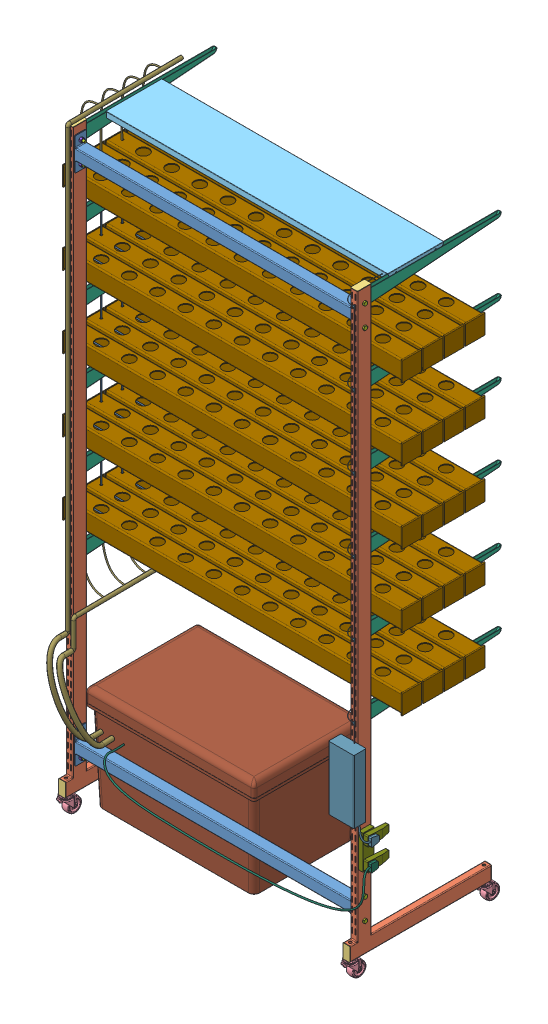
SolidWorks assembly C-L-1000, configuration Default. Lengths in mm.
Overall size (1206 2127.7 609.52).
90 component instances, 16 part files, 241 mates.
Components (placement in the parent):
- TB-1000-1: TB-1000 [Default] at (0 2029.5 0) size (985 115 40)
- TB-1000-2: TB-1000 [Default] at (0 205.5 0) size (985 115 40)
- TSU-F-L-P-1: TSU-F-L-P [Default] at (505 113.5 -25) size (25 2050 500)
- TSU-F-L-P-2: TSU-F-L-P [Default] at (-505 113.5 -25) size (25 2050 500)
- TSU-CAP-1: TSU-CAP [Default] at (-505.1 113.6 -39.9) x (-1 0 0) z (0 0 -1) size (25.2 50.2 6.5)
- TSU-CAP-2: TSU-CAP [Default] at (504.9 113.6 -39.9) x (-1 0 0) z (0 0 -1) size (25.2 50.2 6.5)
- TSU-CAP-3: TSU-CAP [Default] at (505.1 1703.4 -25.1) x (1 0 0) z (0 1 0) size (25.2 50.2 6.5)
- TSU-CAP-4: TSU-CAP [Default] at (504.9 113.6 -360.1) size (25.2 50.2 6.5)
- TSU-CAP-5: TSU-CAP [Default] at (-504.9 1703.4 -25.1) x (1 0 0) z (0 1 0) size (25.2 50.2 6.5)
- TSU-CAP-6: TSU-CAP [Default] at (-504.9 113.6 -360.1) size (25.2 50.2 6.5)
- 2834T320_THREADED-STEM SWIVEL CASTER-1: 2834T320_THREADED-STEM SWIVEL CASTER [2834T32] at (505 82.55 -437.5) x (0 0 -1) z (1 0 0) size (67.73 101.87 56.07)
- 2834T320_THREADED-STEM SWIVEL CASTER-2: 2834T320_THREADED-STEM SWIVEL CASTER [2834T32] at (-505 82.55 37.5) x (0 0 -1) z (1 0 0) size (67.73 101.87 56.07)
- 2834T320_THREADED-STEM SWIVEL CASTER-3: 2834T320_THREADED-STEM SWIVEL CASTER [2834T32] at (505 82.55 37.5) x (0 0 -1) z (1 0 0) size (67.73 101.87 56.07)
- 2834T320_THREADED-STEM SWIVEL CASTER-4: 2834T320_THREADED-STEM SWIVEL CASTER [2834T32] at (-505 82.55 -437.5) x (0 0 -1) z (1 0 0) size (67.73 101.87 56.07)
- TSS-1000-10: TSS-1000 [Default] at (0 818 -199.337) size (1014.96 37.01 331.17)
- TSUB-1: TSUB [Default] at (505 766.5 -25) x (-1 0 0) z (0 0 -1) size (14.07 50.86 484.03)
- TSUB-2: TSUB [Default] at (-505 766.5 -25) x (-1 0 0) z (0 0 -1) size (14.07 50.86 484.03)
- TSUB-3: TSUB [Default] at (-505 1022.5 -25) x (-1 0 0) z (0 0 -1) size (14.07 50.86 484.03)
- TSUB-4: TSUB [Default] at (505 1022.5 -25) x (-1 0 0) z (0 0 -1) size (14.07 50.86 484.03)
- TSS-1000-9: TSS-1000 [Default] at (0 1074 -199.337) size (1014.96 37.01 331.17)
- TSUB-5: TSUB [Default] at (-505 1534.5 -25) x (-1 0 0) z (0 0 -1) size (14.07 50.86 484.03)
- TSUB-6: TSUB [Default] at (505 1534.5 -25) x (-1 0 0) z (0 0 -1) size (14.07 50.86 484.03)
- TSS-1000-3: TSS-1000 [Default] at (0 1586 -199.337) size (1014.96 37.01 331.17)
- TSUB-7: TSUB [Default] at (-505 2046.5 -25) x (-1 0 0) z (0 0 -1) size (14.07 50.86 484.03)
- TSUB-8: TSUB [Default] at (505 2046.5 -25) x (-1 0 0) z (0 0 -1) size (14.07 50.86 484.03)
- TSS-1000-7: TSS-1000 [Default] at (0 2098 -199.337) size (1014.96 37.01 331.17)
- TSUB-9: TSUB [Default] at (-505 1278.5 -25) x (-1 0 0) z (0 0 -1) size (14.07 50.86 484.03)
- TSUB-10: TSUB [Default] at (505 1278.5 -25) x (-1 0 0) z (0 0 -1) size (14.07 50.86 484.03)
- TSS-1000-8: TSS-1000 [Default] at (0 1330 -199.337) size (1014.96 37.01 331.17)
- TSUB-11: TSUB [Default] at (-505 1790.5 -25) x (-1 0 0) z (0 0 -1) size (14.07 50.86 484.03)
- TSUB-12: TSUB [Default] at (505 1790.5 -25) x (-1 0 0) z (0 0 -1) size (14.07 50.86 484.03)
- TSS-1000-6: TSS-1000 [Default] at (0 1842 -199.337) size (1014.96 37.01 331.17)
- hex bolt gradeab2_bsi-10: hex bolt gradeab2_bsi [BS EN 28765 - M8x1 x 45 x 22-N] at (522.8 2067 0) x (-1 0 0) z (0 -0.924225 -0.381849) size (50.3 15.01 13)
- hex bolt gradeab2_bsi-11: hex bolt gradeab2_bsi [BS EN 28765 - M8x1 x 45 x 22-N] at (522.8 1992 0) x (-1 0 0) z (0 -0.999974 0.007224) size (50.3 15.01 13)
- hex bolt gradeab2_bsi-12: hex bolt gradeab2_bsi [BS EN 28765 - M8x1 x 45 x 22-N] at (-522.8 2067 0) size (50.3 15.01 13)
- hex bolt gradeab2_bsi-13: hex bolt gradeab2_bsi [BS EN 28765 - M8x1 x 45 x 22-N] at (-522.8 1992 0) size (50.3 15.01 13)
- hex bolt gradeab2_bsi-14: hex bolt gradeab2_bsi [BS EN 28765 - M8x1 x 45 x 22-N] at (-522.8 168 0) size (50.3 15.01 13)
- hex bolt gradeab2_bsi-15: hex bolt gradeab2_bsi [BS EN 28765 - M8x1 x 45 x 22-N] at (-522.8 243 0) size (50.3 15.01 13)
- hex bolt gradeab2_bsi-16: hex bolt gradeab2_bsi [BS EN 28765 - M8x1 x 45 x 22-N] at (522.8 168 0) x (-1 0 0) z (0 0.924225 0.381849) size (50.3 15.01 13)
- hex bolt gradeab2_bsi-17: hex bolt gradeab2_bsi [BS EN 28765 - M8x1 x 45 x 22-N] at (522.8 243 0) x (-1 0 0) z (0 -0.924225 -0.381849) size (50.3 15.01 13)
- hex nut gradec_bsi-1: hex nut gradec_bsi [BS EN 24034 - M8 - N] at (481.6 2067 0) x (0 0 1) z (-1 0 0) size (13 15.01 7.9)
- hex nut gradec_bsi-2: hex nut gradec_bsi [BS EN 24034 - M8 - N] at (481.6 1992 0) x (0 0 1) z (-1 0 0) size (13 15.01 7.9)
- hex nut gradec_bsi-3: hex nut gradec_bsi [BS EN 24034 - M8 - N] at (-481.6 2067 0) x (0 0 -1) z (1 0 0) size (13 15.01 7.9)
- hex nut gradec_bsi-4: hex nut gradec_bsi [BS EN 24034 - M8 - N] at (-481.6 1992 0) x (0 0.383049 0.923728) z (1 0 0) size (13 15.01 7.9)
- hex nut gradec_bsi-5: hex nut gradec_bsi [BS EN 24034 - M8 - N] at (-481.6 243 0) x (0 0 -1) z (1 0 0) size (13 15.01 7.9)
- hex nut gradec_bsi-6: hex nut gradec_bsi [BS EN 24034 - M8 - N] at (481.6 243 0) x (0 0 1) z (-1 0 0) size (13 15.01 7.9)
- hex nut gradec_bsi-7: hex nut gradec_bsi [BS EN 24034 - M8 - N] at (481.6 168 0) x (0 0 1) z (-1 0 0) size (13 15.01 7.9)
- hex nut gradec_bsi-8: hex nut gradec_bsi [BS EN 24034 - M8 - N] at (-481.6 168 0) x (0 0 -1) z (1 0 0) size (13 15.01 7.9)
- GB-1000-b-30: GB-1000-b [Default] at (0 1106.5 -233.1077) size (1206 70 70)
- GB-600-p-1: GB-600-p [Default] at (-200 1106.5 -233.1077) size (92 218.31 4)
- GB-600-p-2: GB-600-p [Default] at (-200 1106.5 -308.1077) size (92 218.31 4)
- GB-1000-b-29: GB-1000-b [Default] at (0 1106.5 -308.1077) size (1206 70 70)
- GB-600-p-3: GB-600-p [Default] at (-200 1106.5 -83.1077) size (92 218.31 4)
- GB-1000-b-28: GB-1000-b [Default] at (0 1106.5 -83.1077) size (1206 70 70)
- GB-600-p-4: GB-600-p [Default] at (-200 1106.5 -158.1077) size (92 218.31 4)
- GB-1000-b-27: GB-1000-b [Default] at (0 1106.5 -158.1077) size (1206 70 70)
- GB-1000-b-26: GB-1000-b [Default] at (0 850.5 -83.1077) size (1206 70 70)
- GB-1000-b-25: GB-1000-b [Default] at (0 850.5 -158.1077) size (1206 70 70)
- GB-1000-b-24: GB-1000-b [Default] at (0 850.5 -233.1077) size (1206 70 70)
- GB-1000-b-23: GB-1000-b [Default] at (0 850.5 -308.1077) size (1206 70 70)
- GB-1000-b-22: GB-1000-b [Default] at (0 1618.5 -83.1077) size (1206 70 70)
- GB-1000-b-15: GB-1000-b [Default] at (0 1618.5 -158.1077) size (1206 70 70)
- GB-1000-b-21: GB-1000-b [Default] at (0 1618.5 -233.1077) size (1206 70 70)
- GB-1000-b-31: GB-1000-b [Default] at (0 1618.5 -308.1077) size (1206 70 70)
- GB-600-p-5: GB-600-p [Default] at (-200 1618.5 -83.1077) size (92 218.31 4)
- GB-600-p-6: GB-600-p [Default] at (-200 1618.5 -158.1077) size (92 218.31 4)
- GB-600-p-7: GB-600-p [Default] at (-200 1618.5 -233.1077) size (92 218.31 4)
- GB-600-p-8: GB-600-p [Default] at (-200 1618.5 -308.1077) size (92 218.31 4)
- GB-600-p-9: GB-600-p [Default] at (-200 1362.5 -308.1077) size (92 218.31 4)
- GB-600-p-10: GB-600-p [Default] at (-200 1362.5 -233.1077) size (92 218.31 4)
- GB-600-p-11: GB-600-p [Default] at (-200 1362.5 -158.1077) size (92 218.31 4)
- GB-600-p-12: GB-600-p [Default] at (-200 1362.5 -83.1077) size (92 218.31 4)
- GB-1000-b-32: GB-1000-b [Default] at (0 1362.5 -308.1077) size (1206 70 70)
- GB-1000-b-38: GB-1000-b [Default] at (0 1362.5 -233.1077) size (1206 70 70)
- GB-1000-b-33: GB-1000-b [Default] at (0 1362.5 -158.1077) size (1206 70 70)
- GB-1000-b-34: GB-1000-b [Default] at (0 1362.5 -83.1077) size (1206 70 70)
- GB-600-p-13: GB-600-p [Default] at (-200 1874.5 -308.1077) size (92 218.31 4)
- GB-600-p-14: GB-600-p [Default] at (-200 1874.5 -233.1077) size (92 218.31 4)
- GB-600-p-15: GB-600-p [Default] at (-200 1874.5 -158.1077) size (92 218.31 4)
- GB-600-p-16: GB-600-p [Default] at (-200 1874.5 -83.1077) size (92 218.31 4)
- GB-1000-b-35: GB-1000-b [Default] at (0 1874.5 -83.1077) size (1206 70 70)
- GB-1000-b-36: GB-1000-b [Default] at (0 1874.5 -158.1077) size (1206 70 70)
- GB-1000-b-37: GB-1000-b [Default] at (0 1874.5 -233.1077) size (1206 70 70)
- GB-1000-b-39: GB-1000-b [Default] at (0 1874.5 -308.1077) size (1206 70 70)
- WT-1: WT [Default] at (-199.5 320 -225) size (600 370 400)
- Plumbing-1: Plumbing [Default] at (-504.0362 113.5 25.0003) x (0.99996 0 -0.008889) z (0.008889 0 0.99996) size (241.4 2067.5 489.85)
- Wire-1: Wire [Default] at (208.4523 2074.2018 -199.343) x (-1 0 0) z (0 -1 0) size (2 2 1357)
- CCD-1: CCD [Default] at (505 113.5 -25) x (0 0 -1) z (1 0 0) size (82.56 307.09 97.63)
- Pump_LongWire-1: Pump_LongWire [Default] at (-199.5 5 -225) x (1 0 0) z (0 1 0) size (1045.87 220.37 364.08)
- Power Bar-1: Power Bar [Default] at (517.5 113.5 -25) x (0 0 -1) z (1 0 0) size (82.62 120 30)
Mates (geometry in assembly coordinates):
- Coincident5: coincident aligned: plane of TB-1000-2 through (0 205.5 0) normal (1 0 0)
- Coincident6: coincident aligned: plane of TB-1000-2 through (0 205.5 0) normal (0 0 1)
- Tangent1: tangent anti-aligned: torus of 2834T320_THREADED-STEM SWIVEL CASTER-1
- Concentric5: concentric anti-aligned: cylinder of TSU-F-L-P-1 through (505 113.5 -437.5) axis (0 -1 0) radius 5.1; cylinder of 2834T320_THREADED-STEM SWIVEL CASTER-1 through (505 101.6 -437.5) axis (0 1 0) radius 4.7625
- Coincident7: coincident anti-aligned: plane of TB-1000-2 through (492.5 205.5 0) normal (1 0 0); plane of TSU-F-L-P-1 through (492.5 2113.5 -22) normal (-1 0 0)
- Concentric6: concentric anti-aligned: cylinder of TB-1000-2 through (492.5 243 0) axis (-1 0 0) radius 4.5; cylinder of TSU-F-L-P-1 through (490.9 243 0) axis (1 0 0) radius 4.5
- Coincident8: coincident anti-aligned: plane of TSU-F-L-P-1 through (505 63.5 -450) normal (0 -1 0); plane of 2834T320_THREADED-STEM SWIVEL CASTER-1 through (505 63.5 -421.3957) normal (0 1 0)
- Concentric7: concentric anti-aligned: cylinder of TB-1000-1 through (492.5 2067 0) axis (-1 0 0) radius 4.5; cylinder of TSU-F-L-P-1 through (492.5 2067 0) axis (1 0 0) radius 4.5
- Coincident9: coincident anti-aligned: plane of TB-1000-1 through (492.5 2029.5 0) normal (1 0 0); plane of TSU-F-L-P-1 through (492.5 2113.5 -22) normal (-1 0 0)
- Concentric8: concentric aligned: cylinder of TB-1000-2 through (-492.5 168 0) axis (1 0 0) radius 4.5; cylinder of TSU-F-L-P-2 through (-519.1 168 0) axis (1 0 0) radius 4.5
- Coincident10: coincident anti-aligned: plane of TB-1000-2 through (-492.5 205.5 0) normal (-1 0 0); plane of TSU-F-L-P-2 through (-492.5 2113.5 -22) normal (1 0 0)
- Concentric9: concentric anti-aligned: cylinder of TSU-F-L-P-2 through (-505 113.5 -437.5) axis (0 -1 0) radius 5.1; cylinder of 2834T320_THREADED-STEM SWIVEL CASTER-4 through (-505 101.6 -437.5) axis (0 1 0) radius 4.7625
- Concentric10: concentric aligned: cylinder of TB-1000-1 through (-492.5 1992 0) axis (1 0 0) radius 4.5; cylinder of TSU-F-L-P-2 through (-517.5 1992 0) axis (1 0 0) radius 4.5
- Concentric11: concentric aligned: cylinder of TB-1000-1 through (-492.5 2067 0) axis (1 0 0) radius 4.5; cylinder of TSU-F-L-P-2 through (-517.5 2067 0) axis (1 0 0) radius 4.5
- Parallel4: parallel aligned: plane of TSU-F-L-P-1 through (517.5 2113.5 -22) normal (1 0 0); plane of 2834T320_THREADED-STEM SWIVEL CASTER-1 through (516.9062 47.2916 -458.1375) normal (1 0 0)
- Coincident16: coincident anti-aligned: plane of TSU-F-L-P-2 through (-505 63.5 -450) normal (0 -1 0); plane of 2834T320_THREADED-STEM SWIVEL CASTER-4 through (-505 63.5 -421.3957) normal (0 1 0)
- Concentric12: concentric anti-aligned: cylinder of TSU-F-L-P-1 through (505 113.5 37.5) axis (0 -1 0) radius 5.1; cylinder of 2834T320_THREADED-STEM SWIVEL CASTER-3 through (505 101.6 37.5) axis (0 1 0) radius 4.7625
- Coincident17: coincident anti-aligned: plane of TSU-F-L-P-1 through (505 63.5 -450) normal (0 -1 0); plane of 2834T320_THREADED-STEM SWIVEL CASTER-3 through (505 63.5 53.6043) normal (0 1 0)
- Coincident18: coincident aligned: plane of 2834T320_THREADED-STEM SWIVEL CASTER-1 through (516.9062 47.2916 -458.1375) normal (1 0 0); plane of 2834T320_THREADED-STEM SWIVEL CASTER-3 through (516.9062 47.2916 16.8625) normal (1 0 0)
- Concentric13: concentric anti-aligned: cylinder of TSU-F-L-P-2 through (-505 113.5 37.5) axis (0 -1 0) radius 5.1; cylinder of 2834T320_THREADED-STEM SWIVEL CASTER-2 through (-505 101.6 37.5) axis (0 1 0) radius 4.7625
- Coincident19: coincident anti-aligned: plane of TSU-F-L-P-2 through (-505 63.5 -450) normal (0 -1 0); plane of 2834T320_THREADED-STEM SWIVEL CASTER-2 through (-505 63.5 53.6043) normal (0 1 0)
- Parallel6: parallel aligned: plane of TSU-F-L-P-2 through (-517.5 2113.5 -22) normal (-1 0 0); plane of 2834T320_THREADED-STEM SWIVEL CASTER-2 through (-516.9062 47.2916 16.8625) normal (-1 0 0)
- Coincident21: coincident anti-aligned: plane of TSU-F-L-P-1 through (494 2113.5 0) normal (1 0 0); plane of TSU-CAP-4 through (494 113.6 45) normal (-1 0 0)
- Coincident22: coincident anti-aligned: plane of TSU-F-L-P-1 through (514.5 112 -450) normal (0 -1 0); plane of TSU-CAP-4 through (504.9 112 45) normal (0 1 0)
- Coincident23: coincident anti-aligned: plane of TSU-F-L-P-1 through (514.5 110.5 50) normal (0 0 1); plane of TSU-CAP-4 through (504.9 113.6 50) normal (0 0 -1)
- Coincident24: coincident anti-aligned: plane of TSU-F-L-P-2 through (-494 2113.5 0) normal (-1 0 0); plane of TSU-CAP-6 through (-494 113.6 45) normal (1 0 0)
- Coincident25: coincident anti-aligned: plane of TSU-F-L-P-2 through (-495.5 112 -450) normal (0 -1 0); plane of TSU-CAP-6 through (-504.9 112 45) normal (0 1 0)
- Coincident26: coincident anti-aligned: plane of TSU-F-L-P-2 through (-495.5 110.5 50) normal (0 0 1); plane of TSU-CAP-6 through (-504.9 113.6 50) normal (0 0 -1)
- Coincident27: coincident anti-aligned: plane of TSU-F-L-P-1 through (494 2113.5 0) normal (1 0 0); plane of TSU-CAP-2 through (494 113.6 -445) normal (-1 0 0)
- Coincident28: coincident anti-aligned: plane of TSU-F-L-P-1 through (514.5 112 -450) normal (0 -1 0); plane of TSU-CAP-2 through (504.9 112 -445) normal (0 1 0)
- Coincident29: coincident anti-aligned: plane of TSU-F-L-P-1 through (514.5 110.5 -450) normal (0 0 -1); plane of TSU-CAP-2 through (504.9 113.6 -450) normal (0 0 1)
- Coincident30: coincident anti-aligned: plane of TSU-F-L-P-2 through (-516 2113.5 0) normal (1 0 0); plane of TSU-CAP-1 through (-516 113.6 -445) normal (-1 0 0)
- Coincident31: coincident anti-aligned: plane of TSU-F-L-P-2 through (-495.5 112 -450) normal (0 -1 0); plane of TSU-CAP-1 through (-505.1 112 -445) normal (0 1 0)
- Coincident32: coincident anti-aligned: plane of TSU-F-L-P-2 through (-495.5 110.5 -450) normal (0 0 -1); plane of TSU-CAP-1 through (-505.1 113.6 -450) normal (0 0 1)
- Coincident33: coincident anti-aligned: plane of TSU-F-L-P-1 through (516 2113.5 0) normal (-1 0 0); plane of TSU-CAP-3 through (516 2108.5 -25.1) normal (1 0 0)
- Coincident34: coincident anti-aligned: plane of TSU-F-L-P-1 through (514.5 2113.5 -23.5) normal (0 0 1); plane of TSU-CAP-3 through (505.1 2108.5 -23.5) normal (0 0 -1)
- Coincident35: coincident anti-aligned: plane of TSU-F-L-P-1 through (514.5 2113.5 -22) normal (0 1 0); plane of TSU-CAP-3 through (505.1 2113.5 -25.1) normal (0 -1 0)
- Coincident36: coincident anti-aligned: plane of TSU-F-L-P-2 through (-494 2113.5 0) normal (-1 0 0); plane of TSU-CAP-5 through (-494 2108.5 -25.1) normal (1 0 0)
- Coincident37: coincident anti-aligned: plane of TSU-F-L-P-2 through (-495.5 2113.5 -23.5) normal (0 0 1); plane of TSU-CAP-5 through (-504.9 2108.5 -23.5) normal (0 0 -1)
- Coincident38: coincident anti-aligned: plane of TSU-F-L-P-2 through (-495.5 2113.5 -22) normal (0 1 0); plane of TSU-CAP-5 through (-504.9 2113.5 -25.1) normal (0 -1 0)
- Parallel7: parallel aligned: plane of TSU-F-L-P-2 through (-492.5 2113.5 -22) normal (1 0 0); plane of 2834T320_THREADED-STEM SWIVEL CASTER-4 through (-493.0938 47.2916 -458.1375) normal (1 0 0)
- Coincident41: coincident anti-aligned: plane of TSU-F-L-P-1 through (498 273.5 0.001) normal (1 0 0); plane of TSUB-1 through (498 766.5 -25) normal (-1 0 0)
- Coincident42: coincident anti-aligned: plane of TSU-F-L-P-1 through (505 2113.5 -25) normal (0 0 -1); plane of TSUB-1 through (512 766.5 -25) normal (0 0 1)
- Parallel8: parallel: line of TSU-F-L-P-1 through (509 342 -23.5) axis (0 0 -1); plane of TSUB-1 through (498 816.5 -25) normal (0 1 0)
- Coincident44: coincident anti-aligned: plane of TSS-1000-10 through (499.5 798 -199.337) normal (-1 0 0); plane of TSUB-1 through (499.5 766.5 -25) normal (1 0 0)
- Coincident45: coincident anti-aligned: plane of TSS-1000-10 through (501 816.5 -100.837) normal (0 -1 0); plane of TSUB-1 through (498 816.5 -25) normal (0 1 0)
- Coincident46: coincident anti-aligned: plane of TSU-F-L-P-2 through (-512 369.5 0.001) normal (1 0 0); plane of TSUB-2 through (-512 766.5 -25) normal (-1 0 0)
- Coincident47: coincident anti-aligned: plane of TSU-F-L-P-2 through (-505 2113.5 -25) normal (0 0 -1); plane of TSUB-2 through (-512 766.5 -25) normal (0 0 1)
- Coincident48: coincident anti-aligned: plane of TSS-1000-10 through (501 816.5 -100.837) normal (0 -1 0); plane of TSUB-2 through (-512 816.5 -25) normal (0 1 0)
- Coincident49: coincident anti-aligned: plane of TSU-F-L-P-1 through (512 1041.5 0.001) normal (-1 0 0); plane of TSUB-4 through (512 1022.5 -25) normal (1 0 0)
- Coincident50: coincident anti-aligned: plane of TSU-F-L-P-1 through (505 2113.5 -25) normal (0 0 -1); plane of TSUB-4 through (512 1022.5 -25) normal (0 0 1)
- Coincident51: coincident anti-aligned: plane of TSU-F-L-P-2 through (-498 1073.5 0.001) normal (-1 0 0); plane of TSUB-3 through (-498 1022.5 -25) normal (1 0 0)
- Coincident52: coincident anti-aligned: plane of TSU-F-L-P-2 through (-505 2113.5 -25) normal (0 0 -1); plane of TSUB-3 through (-512 1022.5 -25) normal (0 0 1)
- Coincident53: coincident anti-aligned: plane of TSUB-4 through (498 1072.5 -25) normal (0 1 0); plane of TSS-1000-9 through (501 1072.5 -100.837) normal (0 -1 0)
- Coincident54: coincident anti-aligned: plane of TSUB-3 through (-512 1072.5 -25) normal (0 1 0); plane of TSS-1000-9 through (501 1072.5 -100.837) normal (0 -1 0)
- Coincident55: coincident anti-aligned: plane of TSUB-4 through (499.5 1022.5 -25) normal (1 0 0); plane of TSS-1000-9 through (499.5 1054 -199.337) normal (-1 0 0)
- Coincident56: coincident anti-aligned: plane of TSUB-6 through (499.5 1534.5 -25) normal (1 0 0); plane of TSS-1000-3 through (499.5 1566 -199.337) normal (-1 0 0)
- Coincident57: coincident anti-aligned: plane of TSUB-6 through (498 1584.5 -25) normal (0 1 0); plane of TSS-1000-3 through (501 1584.5 -100.837) normal (0 -1 0)
- Coincident58: coincident anti-aligned: plane of TSUB-5 through (-512 1584.5 -25) normal (0 1 0); plane of TSS-1000-3 through (501 1584.5 -100.837) normal (0 -1 0)
- Coincident59: coincident anti-aligned: plane of TSUB-8 through (499.5 2046.5 -25) normal (1 0 0); plane of TSS-1000-7 through (499.5 2078 -199.337) normal (-1 0 0)
- Coincident60: coincident anti-aligned: plane of TSUB-8 through (498 2096.5 -25) normal (0 1 0); plane of TSS-1000-7 through (501 2096.5 -100.837) normal (0 -1 0)
- Coincident61: coincident anti-aligned: plane of TSUB-7 through (-512 2096.5 -25) normal (0 1 0); plane of TSS-1000-7 through (501 2096.5 -100.837) normal (0 -1 0)
- Coincident62: coincident anti-aligned: plane of TSUB-10 through (499.5 1278.5 -25) normal (1 0 0); plane of TSS-1000-8 through (499.5 1310 -199.337) normal (-1 0 0)
- Coincident63: coincident anti-aligned: plane of TSUB-10 through (498 1328.5 -25) normal (0 1 0); plane of TSS-1000-8 through (501 1328.5 -100.837) normal (0 -1 0)
- Coincident64: coincident anti-aligned: plane of TSUB-9 through (-512 1328.5 -25) normal (0 1 0); plane of TSS-1000-8 through (501 1328.5 -100.837) normal (0 -1 0)
- Coincident65: coincident anti-aligned: plane of TSUB-12 through (499.5 1790.5 -25) normal (1 0 0); plane of TSS-1000-6 through (499.5 1822 -199.337) normal (-1 0 0)
- Coincident66: coincident anti-aligned: plane of TSUB-12 through (498 1840.5 -25) normal (0 1 0); plane of TSS-1000-6 through (501 1840.5 -100.837) normal (0 -1 0)
- Coincident67: coincident anti-aligned: plane of TSUB-11 through (-512 1840.5 -25) normal (0 1 0); plane of TSS-1000-6 through (501 1840.5 -100.837) normal (0 -1 0)
- Coincident70: coincident anti-aligned: plane of TSU-F-L-P-1 through (505 2113.5 -25) normal (0 0 -1); plane of TSUB-10 through (498 1278.5 -25) normal (0 0 1)
- Coincident71: coincident anti-aligned: plane of TSU-F-L-P-2 through (-505 2113.5 -25) normal (0 0 -1); plane of TSUB-9 through (-512 1278.5 -25) normal (0 0 1)
- Coincident72: coincident aligned: plane of TSUB-3 through (-498 1022.5 -25) normal (1 0 0); plane of TSUB-9 through (-498 1278.5 -25) normal (1 0 0)
- Coincident73: coincident aligned: plane of TSUB-4 through (498 1022.5 -25) normal (-1 0 0); plane of TSUB-10 through (498 1278.5 -25) normal (-1 0 0)
- Coincident74: coincident anti-aligned: plane of TSU-F-L-P-1 through (505 2113.5 -25) normal (0 0 -1); plane of TSUB-6 through (498 1534.5 -25) normal (0 0 1)
- Coincident75: coincident anti-aligned: plane of TSU-F-L-P-2 through (-505 2113.5 -25) normal (0 0 -1); plane of TSUB-5 through (-512 1534.5 -25) normal (0 0 1)
- Coincident76: coincident aligned: plane of TSUB-5 through (-498 1534.5 -25) normal (1 0 0); plane of TSUB-9 through (-498 1278.5 -25) normal (1 0 0)
- Coincident78: coincident aligned: plane of TSUB-6 through (512 1534.5 -25) normal (1 0 0); plane of TSUB-12 through (512 1790.5 -25) normal (1 0 0)
- Coincident79: coincident aligned: plane of TSUB-6 through (498 1534.5 -25) normal (-1 0 0); plane of TSUB-10 through (498 1278.5 -25) normal (-1 0 0)
- Coincident80: coincident anti-aligned: plane of TSU-F-L-P-1 through (505 2113.5 -25) normal (0 0 -1); plane of TSUB-12 through (498 1790.5 -25) normal (0 0 1)
- Coincident81: coincident anti-aligned: plane of TSU-F-L-P-2 through (-512 1873.5 0.001) normal (1 0 0); plane of TSUB-11 through (-512 1790.5 -25) normal (-1 0 0)
- Coincident82: coincident anti-aligned: plane of TSU-F-L-P-2 through (-505 2113.5 -25) normal (0 0 -1); plane of TSUB-11 through (-512 1790.5 -25) normal (0 0 1)
- Coincident83: coincident anti-aligned: plane of TSU-F-L-P-2 through (-512 1969.5 0.001) normal (1 0 0); plane of TSUB-7 through (-512 2046.5 -25) normal (-1 0 0)
- Coincident84: coincident anti-aligned: plane of TSU-F-L-P-2 through (-505 2113.5 -25) normal (0 0 -1); plane of TSUB-7 through (-512 2046.5 -25) normal (0 0 1)
- Coincident85: coincident anti-aligned: plane of TSU-F-L-P-1 through (498 2001.5 0.001) normal (1 0 0); plane of TSUB-8 through (498 2046.5 -25) normal (-1 0 0)
- Coincident86: coincident anti-aligned: plane of TSU-F-L-P-1 through (505 2113.5 -25) normal (0 0 -1); plane of TSUB-8 through (498 2046.5 -25) normal (0 0 1)
- Coincident89: coincident: line of TSU-F-L-P-1 through (509 2070 -23.5) axis (0 0 -1); plane of TSUB-8 through (533.2603 2070 -25) normal (0 1 0)
- Coincident90: coincident aligned: plane of TSS-1000-7 through (501 2098 -299.337) normal (0 0 -1); plane of TSS-1000-6 through (501 1842 -299.337) normal (0 0 -1)
- Coincident91: coincident aligned: plane of TSS-1000-3 through (501 1586 -299.337) normal (0 0 -1); plane of TSS-1000-6 through (501 1842 -299.337) normal (0 0 -1)
- Coincident93: coincident aligned: plane of TSS-1000-3 through (501 1586 -299.337) normal (0 0 -1); plane of TSS-1000-8 through (501 1330 -299.337) normal (0 0 -1)
- Coincident94: coincident aligned: plane of TSS-1000-9 through (501 1074 -299.337) normal (0 0 -1); plane of TSS-1000-8 through (501 1330 -299.337) normal (0 0 -1)
- Coincident95: coincident aligned: plane of TSS-1000-10 through (501 818 -299.337) normal (0 0 -1); plane of TSS-1000-9 through (501 1074 -299.337) normal (0 0 -1)
- Coincident153: coincident: line of TSU-F-L-P-1 through (512 1814 -23.5) axis (0 0 -1); plane of TSUB-12 through (533.2603 1814 -25) normal (0 1 0)
- Coincident155: coincident: line of TSU-F-L-P-1 through (512 1558 -23.5) axis (0 0 -1); plane of TSUB-6 through (533.2603 1558 -25) normal (0 1 0)
- Coincident157: coincident: line of TSU-F-L-P-1 through (512 1302 -23.5) axis (0 0 -1); plane of TSUB-10 through (533.2603 1302 -25) normal (0 1 0)
- Coincident159: coincident: line of TSU-F-L-P-1 through (512 1046 -23.5) axis (0 0 -1); plane of TSUB-4 through (533.2603 1046 -25) normal (0 1 0)
- Coincident167: coincident: line of TSU-F-L-P-1 through (512 790 -23.5) axis (0 0 -1); plane of TSUB-1 through (533.2603 790 -25) normal (0 1 0)
- Concentric15: concentric aligned: cylinder of TSU-F-L-P-1 through (492.5 2067 0) axis (1 0 0) radius 4.5; cylinder of hex bolt gradeab2_bsi-10 through (522.8 2067 0) axis (1 0 0) radius 4
- Coincident181: coincident anti-aligned: plane of TSU-F-L-P-1 through (517.5 2113.5 -22) normal (1 0 0); plane of hex bolt gradeab2_bsi-10 through (517.5 2069.866 -6.9368) normal (-1 0 0)
- Concentric16: concentric aligned: cylinder of TSU-F-L-P-1 through (492.5 1992 0) axis (1 0 0) radius 4.5; cylinder of hex bolt gradeab2_bsi-11 through (522.8 1992 0) axis (1 0 0) radius 4
- Coincident182: coincident anti-aligned: plane of TSU-F-L-P-1 through (517.5 2113.5 -22) normal (1 0 0); plane of hex bolt gradeab2_bsi-11 through (517.5 1991.9458 -7.5054) normal (-1 0 0)
- Concentric17: concentric anti-aligned: cylinder of TB-1000-1 through (-492.5 2067 0) axis (1 0 0) radius 4.5; cylinder of hex bolt gradeab2_bsi-12 through (-522.8 2067 0) axis (-1 0 0) radius 4
- Coincident183: coincident anti-aligned: plane of TSU-F-L-P-2 through (-517.5 2113.5 -22) normal (-1 0 0); plane of hex bolt gradeab2_bsi-12 through (-517.5 2074.5056 0) normal (1 0 0)
- Concentric18: concentric anti-aligned: cylinder of TB-1000-1 through (-492.5 1992 0) axis (1 0 0) radius 4.5; cylinder of hex bolt gradeab2_bsi-13 through (-522.8 1992 0) axis (-1 0 0) radius 4
- Coincident184: coincident anti-aligned: plane of TSU-F-L-P-2 through (-517.5 2113.5 -22) normal (-1 0 0); plane of hex bolt gradeab2_bsi-13 through (-517.5 1999.5056 0) normal (1 0 0)
- Concentric19: concentric anti-aligned: cylinder of TB-1000-2 through (-492.5 243 0) axis (1 0 0) radius 4.5; cylinder of hex bolt gradeab2_bsi-15 through (-522.8 243 0) axis (-1 0 0) radius 4
- Coincident185: coincident anti-aligned: plane of TSU-F-L-P-2 through (-517.5 2113.5 -22) normal (-1 0 0); plane of hex bolt gradeab2_bsi-15 through (-517.5 250.5056 0) normal (1 0 0)
- Concentric20: concentric anti-aligned: cylinder of TB-1000-2 through (-492.5 168 0) axis (1 0 0) radius 4.5; cylinder of hex bolt gradeab2_bsi-14 through (-522.8 168 0) axis (-1 0 0) radius 4
- Coincident186: coincident anti-aligned: plane of TSU-F-L-P-2 through (-517.5 2113.5 -22) normal (-1 0 0); plane of hex bolt gradeab2_bsi-14 through (-517.5 175.5056 0) normal (1 0 0)
- Concentric21: concentric anti-aligned: cylinder of TB-1000-2 through (492.5 243 0) axis (-1 0 0) radius 4.5; cylinder of hex bolt gradeab2_bsi-17 through (522.8 243 0) axis (1 0 0) radius 4
- Coincident187: coincident anti-aligned: plane of TSU-F-L-P-1 through (517.5 2113.5 -22) normal (1 0 0); plane of hex bolt gradeab2_bsi-17 through (517.5 245.866 -6.9368) normal (-1 0 0)
- Concentric22: concentric aligned: cylinder of TSU-F-L-P-1 through (490.9 168 0) axis (1 0 0) radius 4.5; cylinder of hex bolt gradeab2_bsi-16 through (522.8 168 0) axis (1 0 0) radius 4
- Coincident188: coincident anti-aligned: plane of TSU-F-L-P-1 through (517.5 2113.5 -22) normal (1 0 0); plane of hex bolt gradeab2_bsi-16 through (517.5 165.134 6.9368) normal (-1 0 0)
- Concentric23: concentric anti-aligned: cylinder of hex bolt gradeab2_bsi-10 through (522.8 2067 0) axis (1 0 0) radius 4; cylinder of hex nut gradec_bsi-1 through (489.5 2067 0) axis (-1 0 0) radius 3.4
- Coincident189: coincident anti-aligned: plane of TB-1000-1 through (489.5 2029.5 0) normal (-1 0 0); plane of hex nut gradec_bsi-1 through (489.5 2074.5056 0) normal (1 0 0)
- Concentric24: concentric anti-aligned: cylinder of hex bolt gradeab2_bsi-11 through (522.8 1992 0) axis (1 0 0) radius 4; cylinder of hex nut gradec_bsi-2 through (489.5 1992 0) axis (-1 0 0) radius 3.4
- Coincident190: coincident anti-aligned: plane of TB-1000-1 through (489.5 2029.5 0) normal (-1 0 0); plane of hex nut gradec_bsi-2 through (489.5 1999.5056 0) normal (1 0 0)
- Concentric25: concentric anti-aligned: cylinder of hex bolt gradeab2_bsi-12 through (-522.8 2067 0) axis (-1 0 0) radius 4; cylinder of hex nut gradec_bsi-3 through (-489.5 2067 0) axis (1 0 0) radius 3.4
- Coincident191: coincident anti-aligned: plane of TB-1000-1 through (-489.5 2029.5 0) normal (1 0 0); plane of hex nut gradec_bsi-3 through (-489.5 2074.5056 0) normal (-1 0 0)
- Concentric26: concentric anti-aligned: cylinder of hex bolt gradeab2_bsi-13 through (-522.8 1992 0) axis (-1 0 0) radius 4; cylinder of hex nut gradec_bsi-4 through (-489.5 1992 0) axis (1 0 0) radius 3.4
- Coincident192: coincident anti-aligned: plane of TB-1000-1 through (-489.5 2029.5 0) normal (1 0 0); plane of hex nut gradec_bsi-4 through (-489.5 1985.0669 2.875) normal (-1 0 0)
- Concentric27: concentric anti-aligned: cylinder of hex bolt gradeab2_bsi-15 through (-522.8 243 0) axis (-1 0 0) radius 4; cylinder of hex nut gradec_bsi-5 through (-489.5 243 0) axis (1 0 0) radius 3.4
- Coincident193: coincident anti-aligned: plane of TB-1000-2 through (-489.5 205.5 0) normal (1 0 0); plane of hex nut gradec_bsi-5 through (-489.5 250.5056 0) normal (-1 0 0)
- Concentric28: concentric anti-aligned: cylinder of hex bolt gradeab2_bsi-14 through (-522.8 168 0) axis (-1 0 0) radius 4; cylinder of hex nut gradec_bsi-8 through (-489.5 168 0) axis (1 0 0) radius 3.4
- Coincident194: coincident anti-aligned: plane of TB-1000-2 through (-489.5 205.5 0) normal (1 0 0); plane of hex nut gradec_bsi-8 through (-489.5 175.5056 0) normal (-1 0 0)
- Concentric29: concentric anti-aligned: cylinder of hex bolt gradeab2_bsi-17 through (522.8 243 0) axis (1 0 0) radius 4; cylinder of hex nut gradec_bsi-6 through (489.5 243 0) axis (-1 0 0) radius 3.4
- Concentric30: concentric anti-aligned: cylinder of hex bolt gradeab2_bsi-16 through (522.8 168 0) axis (1 0 0) radius 4; cylinder of hex nut gradec_bsi-7 through (489.5 168 0) axis (-1 0 0) radius 3.4
- Coincident195: coincident anti-aligned: plane of TB-1000-2 through (489.5 205.5 0) normal (-1 0 0); plane of hex nut gradec_bsi-6 through (489.5 250.5056 0) normal (1 0 0)
- Coincident196: coincident anti-aligned: plane of TB-1000-2 through (489.5 205.5 0) normal (-1 0 0); plane of hex nut gradec_bsi-7 through (489.5 175.5056 0) normal (1 0 0)
- Concentric31: concentric aligned: cylinder of GB-1000-b-24 through (-575 815.499 -233.1077) axis (0 1 0) radius 4; cylinder of GB-600-p-1 through (-575 877 -233.1077) axis (0 1 0) radius 2
- Distance1: distance = 10 mm aligned: plane of GB-600-p-1 through (-575 1087 -233.1077) normal (0 1 0); plane of GB-1000-b-30 through (600 1077 -200.6077) normal (0 1 0)
- Parallel10: parallel anti-aligned: plane of TSU-F-L-P-1 through (505 2113.5 -25) normal (0 0 -1); plane of GB-1000-b-30 through (600 1074 -200.6077) normal (0 0 1)
- Coincident201: coincident aligned: plane of GB-1000-b-30 through (0 1106.5 -233.1077) normal (1 0 0)
- Coincident202: coincident anti-aligned: plane of TSS-1000-9 through (501 1074 -99.337) normal (0 1 0); plane of GB-1000-b-30 through (600 1074 -200.6077) normal (0 -1 0)
- Concentric32: concentric aligned: cylinder of GB-600-p-2 through (-575 877 -308.1077) axis (0 1 0) radius 2; cylinder of GB-1000-b-29 through (-575 1071.499 -308.1077) axis (0 1 0) radius 4
- Distance2: distance = 10 mm aligned: plane of GB-600-p-2 through (-575 1087 -308.1077) normal (0 1 0); plane of GB-1000-b-29 through (600 1077 -275.6077) normal (0 1 0)
- Concentric33: concentric aligned: cylinder of GB-600-p-3 through (-575 877 -83.1077) axis (0 1 0) radius 2; cylinder of GB-1000-b-28 through (-575 1071.499 -83.1077) axis (0 1 0) radius 4
- Distance3: distance = 10 mm aligned: plane of GB-600-p-3 through (-575 1087 -83.1077) normal (0 1 0); plane of GB-1000-b-28 through (600 1077 -50.6077) normal (0 1 0)
- Concentric34: concentric aligned: cylinder of GB-600-p-4 through (-575 877 -158.1077) axis (0 1 0) radius 2; cylinder of GB-1000-b-27 through (-575 1071.499 -158.1077) axis (0 1 0) radius 4
- Distance4: distance = 10 mm aligned: plane of GB-600-p-4 through (-575 1087 -158.1077) normal (0 1 0); plane of GB-1000-b-27 through (600 1077 -125.6077) normal (0 1 0)
- Coincident203: coincident anti-aligned: plane of TSS-1000-9 through (501 1074 -99.337) normal (0 1 0); plane of GB-1000-b-29 through (600 1074 -275.6077) normal (0 -1 0)
- Coincident204: coincident anti-aligned: plane of TSS-1000-9 through (501 1074 -99.337) normal (0 1 0); plane of GB-1000-b-27 through (600 1074 -125.6077) normal (0 -1 0)
- Coincident205: coincident anti-aligned: plane of TSS-1000-9 through (501 1074 -99.337) normal (0 1 0); plane of GB-1000-b-28 through (600 1074 -50.6077) normal (0 -1 0)
- Coincident206: coincident aligned: plane of GB-1000-b-30 through (603 1106.5 -233.1077) normal (1 0 0); plane of GB-1000-b-27 through (603 1106.5 -158.1077) normal (1 0 0)
- Coincident207: coincident aligned: plane of GB-1000-b-28 through (603 1106.5 -83.1077) normal (1 0 0); plane of GB-1000-b-27 through (603 1106.5 -158.1077) normal (1 0 0)
- Coincident208: coincident aligned: plane of GB-1000-b-30 through (603 1106.5 -233.1077) normal (1 0 0); plane of GB-1000-b-29 through (603 1106.5 -308.1077) normal (1 0 0)
- Distance5: distance = 10 mm anti-aligned: plane of GB-1000-b-27 through (600 1074 -190.6077) normal (0 0 -1); plane of GB-1000-b-30 through (600 1074 -200.6077) normal (0 0 1)
- Distance6: distance = 10 mm anti-aligned: plane of GB-1000-b-27 through (600 1074 -125.6077) normal (0 0 1); plane of GB-1000-b-28 through (600 1074 -115.6077) normal (0 0 -1)
- Distance7: distance = 10 mm anti-aligned: plane of GB-1000-b-30 through (600 1074 -265.6077) normal (0 0 -1); plane of GB-1000-b-29 through (600 1074 -275.6077) normal (0 0 1)
- Distance8: distance = 10 mm anti-aligned: plane of GB-1000-b-25 through (600 818 -125.6077) normal (0 0 1); plane of GB-1000-b-26 through (600 818 -115.6077) normal (0 0 -1)
- Distance9: distance = 10 mm anti-aligned: plane of GB-1000-b-25 through (600 818 -190.6077) normal (0 0 -1); plane of GB-1000-b-24 through (600 818 -200.6077) normal (0 0 1)
- Coincident212: coincident aligned: plane of GB-1000-b-26 through (603 850.5 -83.1077) normal (1 0 0); plane of GB-1000-b-25 through (603 850.5 -158.1077) normal (1 0 0)
- Coincident213: coincident aligned: plane of GB-1000-b-24 through (603 850.5 -233.1077) normal (1 0 0); plane of GB-1000-b-23 through (603 850.5 -308.1077) normal (1 0 0)
- Coincident214: coincident aligned: plane of GB-1000-b-25 through (603 850.5 -158.1077) normal (1 0 0); plane of GB-1000-b-24 through (603 850.5 -233.1077) normal (1 0 0)
- Distance10: distance = 10 mm anti-aligned: plane of GB-1000-b-24 through (600 818 -265.6077) normal (0 0 -1); plane of GB-1000-b-23 through (600 818 -275.6077) normal (0 0 1)
- Coincident215: coincident aligned: plane of GB-1000-b-24 through (600 818 -200.6077) normal (0 -1 0); plane of GB-1000-b-23 through (600 818 -275.6077) normal (0 -1 0)
- Coincident216: coincident aligned: plane of GB-1000-b-25 through (600 818 -125.6077) normal (0 -1 0); plane of GB-1000-b-24 through (600 818 -200.6077) normal (0 -1 0)
- Coincident217: coincident aligned: plane of GB-1000-b-26 through (600 818 -50.6077) normal (0 -1 0); plane of GB-1000-b-25 through (600 818 -125.6077) normal (0 -1 0)
- Coincident218: coincident anti-aligned: plane of TSS-1000-10 through (501 818 -99.337) normal (0 1 0); plane of GB-1000-b-24 through (600 818 -200.6077) normal (0 -1 0)
- Concentric35: concentric aligned: cylinder of GB-600-p-2 through (-575 877 -308.1077) axis (0 1 0) radius 2; cylinder of GB-1000-b-23 through (-575 815.499 -308.1077) axis (0 1 0) radius 4
- Concentric36: concentric aligned: cylinder of GB-1000-b-22 through (-575 1583.499 -83.1077) axis (0 1 0) radius 4; cylinder of GB-600-p-5 through (-575 1389 -83.1077) axis (0 1 0) radius 2
- Distance11: distance = 10 mm anti-aligned: plane of GB-1000-b-15 through (600 1586 -125.6077) normal (0 0 1); plane of GB-1000-b-22 through (600 1586 -115.6077) normal (0 0 -1)
- Concentric37: concentric aligned: cylinder of GB-1000-b-31 through (-575 1583.499 -308.1077) axis (0 1 0) radius 4; cylinder of GB-600-p-8 through (-575 1389 -308.1077) axis (0 1 0) radius 2
- Concentric38: concentric aligned: cylinder of GB-1000-b-21 through (-575 1583.499 -233.1077) axis (0 1 0) radius 4; cylinder of GB-600-p-7 through (-575 1389 -233.1077) axis (0 1 0) radius 2
- Distance12: distance = 10 mm aligned: plane of GB-600-p-7 through (-575 1599 -233.1077) normal (0 1 0); plane of GB-1000-b-21 through (600 1589 -200.6077) normal (0 1 0)
- Distance13: distance = 10 mm anti-aligned: plane of GB-1000-b-15 through (600 1586 -190.6077) normal (0 0 -1); plane of GB-1000-b-21 through (600 1586 -200.6077) normal (0 0 1)
- Concentric39: concentric aligned: cylinder of GB-1000-b-15 through (-575 1583.499 -158.1077) axis (0 1 0) radius 4; cylinder of GB-600-p-6 through (-575 1389 -158.1077) axis (0 1 0) radius 2
- Distance14: distance = 10 mm aligned: plane of GB-600-p-8 through (-575 1599 -308.1077) normal (0 1 0); plane of GB-1000-b-31 through (600 1589 -275.6077) normal (0 1 0)
- Distance15: distance = 10 mm aligned: plane of GB-600-p-5 through (-575 1599 -83.1077) normal (0 1 0); plane of GB-1000-b-22 through (600 1589 -50.6077) normal (0 1 0)
- Distance16: distance = 10 mm aligned: plane of GB-600-p-6 through (-575 1599 -158.1077) normal (0 1 0); plane of GB-1000-b-15 through (600 1589 -125.6077) normal (0 1 0)
- Coincident220: coincident aligned: plane of GB-1000-b-22 through (603 1618.5 -83.1077) normal (1 0 0); plane of GB-1000-b-15 through (603 1618.5 -158.1077) normal (1 0 0)
- Coincident221: coincident aligned: plane of GB-1000-b-21 through (603 1618.5 -233.1077) normal (1 0 0); plane of GB-1000-b-31 through (603 1618.5 -308.1077) normal (1 0 0)
- Coincident222: coincident aligned: plane of GB-1000-b-15 through (603 1618.5 -158.1077) normal (1 0 0); plane of GB-1000-b-21 through (603 1618.5 -233.1077) normal (1 0 0)
- Distance17: distance = 10 mm anti-aligned: plane of GB-1000-b-21 through (600 1586 -265.6077) normal (0 0 -1); plane of GB-1000-b-31 through (600 1586 -275.6077) normal (0 0 1)
- Coincident223: coincident aligned: plane of GB-1000-b-31 through (600 1586 -275.6077) normal (0 -1 0); plane of GB-1000-b-22 through (600 1586 -50.6077) normal (0 -1 0)
- Coincident224: coincident aligned: plane of GB-1000-b-22 through (600 1586 -50.6077) normal (0 -1 0); plane of GB-1000-b-15 through (600 1586 -125.6077) normal (0 -1 0)
- Coincident225: coincident aligned: plane of GB-1000-b-15 through (600 1586 -125.6077) normal (0 -1 0); plane of GB-1000-b-21 through (600 1586 -200.6077) normal (0 -1 0)
- Coincident226: coincident aligned: plane of GB-1000-b-33 through (600 1330 -125.6077) normal (0 -1 0); plane of GB-1000-b-34 through (600 1330 -50.6077) normal (0 -1 0)
- Coincident227: coincident aligned: plane of GB-1000-b-38 through (600 1330 -200.6077) normal (0 -1 0); plane of GB-1000-b-33 through (600 1330 -125.6077) normal (0 -1 0)
- Coincident228: coincident aligned: plane of GB-1000-b-38 through (603 1362.5 -233.1077) normal (1 0 0); plane of GB-1000-b-33 through (603 1362.5 -158.1077) normal (1 0 0)
- Distance18: distance = 10 mm anti-aligned: plane of GB-1000-b-38 through (600 1330 -265.6077) normal (0 0 -1); plane of GB-1000-b-32 through (600 1330 -275.6077) normal (0 0 1)
- Coincident229: coincident aligned: plane of GB-1000-b-32 through (600 1330 -275.6077) normal (0 -1 0); plane of GB-1000-b-34 through (600 1330 -50.6077) normal (0 -1 0)
- Concentric40: concentric aligned: cylinder of GB-600-p-10 through (-575 1133 -233.1077) axis (0 1 0) radius 2; cylinder of GB-1000-b-38 through (-575 1327.499 -233.1077) axis (0 1 0) radius 4
- Distance19: distance = 10 mm aligned: plane of GB-600-p-11 through (-575 1343 -158.1077) normal (0 1 0); plane of GB-1000-b-33 through (600 1333 -125.6077) normal (0 1 0)
- Concentric41: concentric aligned: cylinder of GB-600-p-12 through (-575 1133 -83.1077) axis (0 1 0) radius 2; cylinder of GB-1000-b-34 through (-575 1327.499 -83.1077) axis (0 1 0) radius 4
- Distance20: distance = 10 mm aligned: plane of GB-600-p-12 through (-575 1343 -83.1077) normal (0 1 0); plane of GB-1000-b-34 through (600 1333 -50.6077) normal (0 1 0)
- Distance21: distance = 10 mm anti-aligned: plane of GB-1000-b-33 through (600 1330 -125.6077) normal (0 0 1); plane of GB-1000-b-34 through (600 1330 -115.6077) normal (0 0 -1)
- Coincident230: coincident aligned: plane of GB-1000-b-33 through (603 1362.5 -158.1077) normal (1 0 0); plane of GB-1000-b-34 through (603 1362.5 -83.1077) normal (1 0 0)
- Distance22: distance = 10 mm anti-aligned: plane of GB-1000-b-33 through (600 1330 -190.6077) normal (0 0 -1); plane of GB-1000-b-38 through (600 1330 -200.6077) normal (0 0 1)
- Concentric42: concentric aligned: cylinder of GB-600-p-9 through (-575 1133 -308.1077) axis (0 1 0) radius 2; cylinder of GB-1000-b-32 through (-575 1327.499 -308.1077) axis (0 1 0) radius 4
- Distance23: distance = 10 mm aligned: plane of GB-600-p-9 through (-575 1343 -308.1077) normal (0 1 0); plane of GB-1000-b-32 through (600 1333 -275.6077) normal (0 1 0)
- Distance24: distance = 10 mm aligned: plane of GB-600-p-10 through (-575 1343 -233.1077) normal (0 1 0); plane of GB-1000-b-38 through (600 1333 -200.6077) normal (0 1 0)
- Concentric43: concentric aligned: cylinder of GB-600-p-11 through (-575 1133 -158.1077) axis (0 1 0) radius 2; cylinder of GB-1000-b-33 through (-575 1327.499 -158.1077) axis (0 1 0) radius 4
- Coincident231: coincident aligned: plane of GB-1000-b-32 through (603 1362.5 -308.1077) normal (1 0 0); plane of GB-1000-b-38 through (603 1362.5 -233.1077) normal (1 0 0)
- Coincident232: coincident anti-aligned: plane of TSS-1000-8 through (501 1330 -99.337) normal (0 1 0); plane of GB-1000-b-32 through (600 1330 -275.6077) normal (0 -1 0)
- Coincident233: coincident aligned: plane of GB-1000-b-29 through (600 1074 -340.6077) normal (0 0 -1); plane of GB-1000-b-32 through (600 1330 -340.6077) normal (0 0 -1)
- Coincident234: coincident aligned: plane of GB-1000-b-29 through (603 1106.5 -308.1077) normal (1 0 0); plane of GB-1000-b-32 through (603 1362.5 -308.1077) normal (1 0 0)
- Coincident235: coincident anti-aligned: plane of TSS-1000-3 through (501 1586 -99.337) normal (0 1 0); plane of GB-1000-b-31 through (600 1586 -275.6077) normal (0 -1 0)
- Coincident236: coincident aligned: plane of GB-1000-b-32 through (-603 1362.5 -308.1077) normal (-1 0 0); plane of GB-1000-b-31 through (-603 1618.5 -308.1077) normal (-1 0 0)
- Coincident237: coincident aligned: plane of GB-1000-b-31 through (600 1586 -340.6077) normal (0 0 -1); plane of GB-1000-b-32 through (600 1330 -340.6077) normal (0 0 -1)
- Coincident238: coincident aligned: plane of GB-1000-b-35 through (600 1842 -50.6077) normal (0 -1 0); plane of GB-1000-b-36 through (600 1842 -125.6077) normal (0 -1 0)
- Coincident239: coincident aligned: plane of GB-1000-b-36 through (600 1842 -125.6077) normal (0 -1 0); plane of GB-1000-b-37 through (600 1842 -200.6077) normal (0 -1 0)
- Coincident240: coincident aligned: plane of GB-1000-b-36 through (603 1874.5 -158.1077) normal (1 0 0); plane of GB-1000-b-37 through (603 1874.5 -233.1077) normal (1 0 0)
- Distance25: distance = 10 mm anti-aligned: plane of GB-1000-b-37 through (600 1842 -265.6077) normal (0 0 -1); plane of GB-1000-b-39 through (600 1842 -275.6077) normal (0 0 1)
- Coincident241: coincident aligned: plane of GB-1000-b-35 through (600 1842 -50.6077) normal (0 -1 0); plane of GB-1000-b-39 through (600 1842 -275.6077) normal (0 -1 0)
- Concentric44: concentric aligned: cylinder of GB-600-p-14 through (-575 1645 -233.1077) axis (0 1 0) radius 2; cylinder of GB-1000-b-37 through (-575 1839.499 -233.1077) axis (0 1 0) radius 4
- Distance26: distance = 10 mm aligned: plane of GB-600-p-15 through (-575 1855 -158.1077) normal (0 1 0); plane of GB-1000-b-36 through (600 1845 -125.6077) normal (0 1 0)
- Concentric45: concentric aligned: cylinder of GB-600-p-16 through (-575 1645 -83.1077) axis (0 1 0) radius 2; cylinder of GB-1000-b-35 through (-575 1839.499 -83.1077) axis (0 1 0) radius 4
- Distance27: distance = 10 mm aligned: plane of GB-600-p-16 through (-575 1855 -83.1077) normal (0 1 0); plane of GB-1000-b-35 through (600 1845 -50.6077) normal (0 1 0)
- Distance28: distance = 10 mm anti-aligned: plane of GB-1000-b-36 through (600 1842 -125.6077) normal (0 0 1); plane of GB-1000-b-35 through (600 1842 -115.6077) normal (0 0 -1)
- Coincident242: coincident aligned: plane of GB-1000-b-35 through (603 1874.5 -83.1077) normal (1 0 0); plane of GB-1000-b-36 through (603 1874.5 -158.1077) normal (1 0 0)
- Distance29: distance = 10 mm anti-aligned: plane of GB-1000-b-36 through (600 1842 -190.6077) normal (0 0 -1); plane of GB-1000-b-37 through (600 1842 -200.6077) normal (0 0 1)
- Concentric46: concentric aligned: cylinder of GB-600-p-13 through (-575 1645 -308.1077) axis (0 1 0) radius 2; cylinder of GB-1000-b-39 through (-575 1839.499 -308.1077) axis (0 1 0) radius 4
- Distance30: distance = 10 mm aligned: plane of GB-600-p-13 through (-575 1855 -308.1077) normal (0 1 0); plane of GB-1000-b-39 through (600 1845 -275.6077) normal (0 1 0)
- Distance31: distance = 10 mm aligned: plane of GB-600-p-14 through (-575 1855 -233.1077) normal (0 1 0); plane of GB-1000-b-37 through (600 1845 -200.6077) normal (0 1 0)
- Concentric47: concentric aligned: cylinder of GB-600-p-15 through (-575 1645 -158.1077) axis (0 1 0) radius 2; cylinder of GB-1000-b-36 through (-575 1839.499 -158.1077) axis (0 1 0) radius 4
- Coincident243: coincident aligned: plane of GB-1000-b-37 through (603 1874.5 -233.1077) normal (1 0 0); plane of GB-1000-b-39 through (603 1874.5 -308.1077) normal (1 0 0)
- Coincident244: coincident anti-aligned: plane of TSS-1000-6 through (501 1842 -99.337) normal (0 1 0); plane of GB-1000-b-39 through (600 1842 -275.6077) normal (0 -1 0)
- Coincident245: coincident aligned: plane of GB-1000-b-31 through (600 1586 -340.6077) normal (0 0 -1); plane of GB-1000-b-39 through (600 1842 -340.6077) normal (0 0 -1)
- Coincident246: coincident aligned: plane of GB-1000-b-31 through (-603 1618.5 -308.1077) normal (-1 0 0); plane of GB-1000-b-39 through (-603 1874.5 -308.1077) normal (-1 0 0)
- Coincident247: coincident anti-aligned: plane of Part3-1 through (-199.5 0 -225) normal (0 -1 0)
- Coincident249: coincident anti-aligned: plane of TSU-F-L-P-1 through (505 2113.5 -25) normal (0 0 -1); plane of Part3-1 through (-199.5 370 -25) normal (0 0 1)
- Coincident250: coincident aligned: plane of GB-1000-b-29 through (603 1106.5 -308.1077) normal (1 0 0); plane of GB-1000-b-23 through (603 850.5 -308.1077) normal (1 0 0)
- InPlace3: in place: plane of ? through (305 113.5 -25) normal (1 0 0); plane of ? through (305 113.5 -25) normal (1 0 0); moOrthogonalPlaneRef_w of ? through (305 113.5 -25) normal (1 0 0); plane of ? through (305 113.5 -25) normal (0 1 0); plane of ? through (305 113.5 -25) normal (1 0 0); plane of ? through (305 113.5 -25) normal (0 0 -1); plane of TSU-F-L-P-1 through (505 113.5 -25) normal (1 0 0); unknown of CCD-1
- Coincident254: coincident aligned: plane of TSU-F-L-P-1; plane of CCD-1
- Coincident255: coincident aligned: moOrthogonalPlaneRef_w of TSU-F-L-P-1; plane of Part2-1 through (505 113.5 -25) normal (0 1 0)
- Coincident256: coincident anti-aligned: moOrthogonalPlaneRef_w of TSU-F-L-P-1 through (-25 0 0) axis (1 0 0); plane of Part2-1 through (505 113.5 -25) normal (0 0 -1)
- InPlace4: in place: plane of ? through (0 5 -225) normal (0 1 0); plane of ? through (0 5 0) normal (0 1 0); plane of ? through (0 5 -225) normal (0 1 0); plane of ? through (0 5 0) normal (0 0 -1); plane of ? through (0 5 -225) normal (0 1 0); plane of ? through (0 5 0) normal (1 0 0); plane of WT-1 through (-199.5 5 -225) normal (0 1 0); unknown of Pump_LongWire-1
- Coincident257: coincident aligned: plane of WT-1; plane of Pump_LongWire-1
- Coincident258: coincident aligned: moOrthogonalPlaneRef_w of Part3-1 through (-199.5 5 -225) normal (0 0 -1); plane of ele-1 through (-199.5 5 -225) normal (0 0 -1)
- Coincident259: coincident anti-aligned: moOrthogonalPlaneRef_w of Part3-1 through (-199.5 5 -225) normal (-1 0 0); plane of ele-1 through (-199.5 5 -225) normal (1 0 0)
- InPlace5: in place: plane of ? through (317.5 2113.5 -22) normal (1 0 0); plane of ? through (317.5 0 0) normal (1 0 0); plane of ? through (317.5 2113.5 -22) normal (1 0 0); plane of ? through (317.5 0 0) normal (0 1 0); plane of ? through (317.5 2113.5 -22) normal (1 0 0); plane of ? through (317.5 0 0) normal (0 0 -1); plane of TSU-F-L-P-1 through (517.5 2113.5 -22) normal (1 0 0); unknown of Power Bar-1
- Coincident260: coincident aligned: plane of TSU-F-L-P-1; plane of Power Bar-1
- Coincident261: coincident aligned: moOrthogonalPlaneRef_w of TSU-F-L-P-1 through (517.5 113.5 -25) normal (0 1 0); plane of power brick-1 through (517.5 113.5 -25) normal (0 1 0)
- Coincident262: coincident anti-aligned: moOrthogonalPlaneRef_w of TSU-F-L-P-1 through (517.5 113.5 -25) normal (0 0 1); plane of power brick-1 through (517.5 113.5 -25) normal (0 0 -1)
- Concentric49: concentric anti-aligned: circle of GB-1000-b-26; circle of Part5-1
- Tangent3: tangent anti-aligned: plane of TSU-F-L-P-2 through (-505 2113.5 25) normal (0 0 1); cylinder of Part5-1 through (-503.9798 2115 31.35) axis (0 -1 0) radius 6.35
- Tangent4: tangent anti-aligned: plane of TSU-CAP-5 through (-504.9 2115 -25.1) normal (0 1 0); cylinder of Part5-1 through (-507.5918 2121.35 -374.9839) axis (0.008889 0 0.99996) radius 6.35
- Tangent5: tangent aligned: cylinder of GB-1000-b-39 through (-575 1839.499 -308.1077) axis (0 1 0) radius 4; face of Plumbing-1
- Distance32: distance = 12.5 mm aligned: plane of Part3-1 through (-499.5 370 -225) normal (-1 0 0); plane of TSUB-2 through (-512 766.5 -25) normal (-1 0 0)
- Tangent6: tangent aligned: plane of TSS-1000-10 through (513.9572 818 29.8309) normal (1 0 0); cylinder of Part1-1 through (512.9572 717.2018 30.8309) axis (0 1 0) radius 1
- Tangent7: tangent aligned: plane of TSS-1000-10 through (0 818 31.8309) normal (0 0 1); cylinder of Part1-1 through (512.9572 717.2018 30.8309) axis (0 1 0) radius 1
- Coincident254: coincident aligned: plane of TSS-1000-7 through (0 2074.2018 29.8309) normal (0 1 0); plane of Part1-1 through (512.9572 2074.2018 30.8309) normal (0 1 0)
